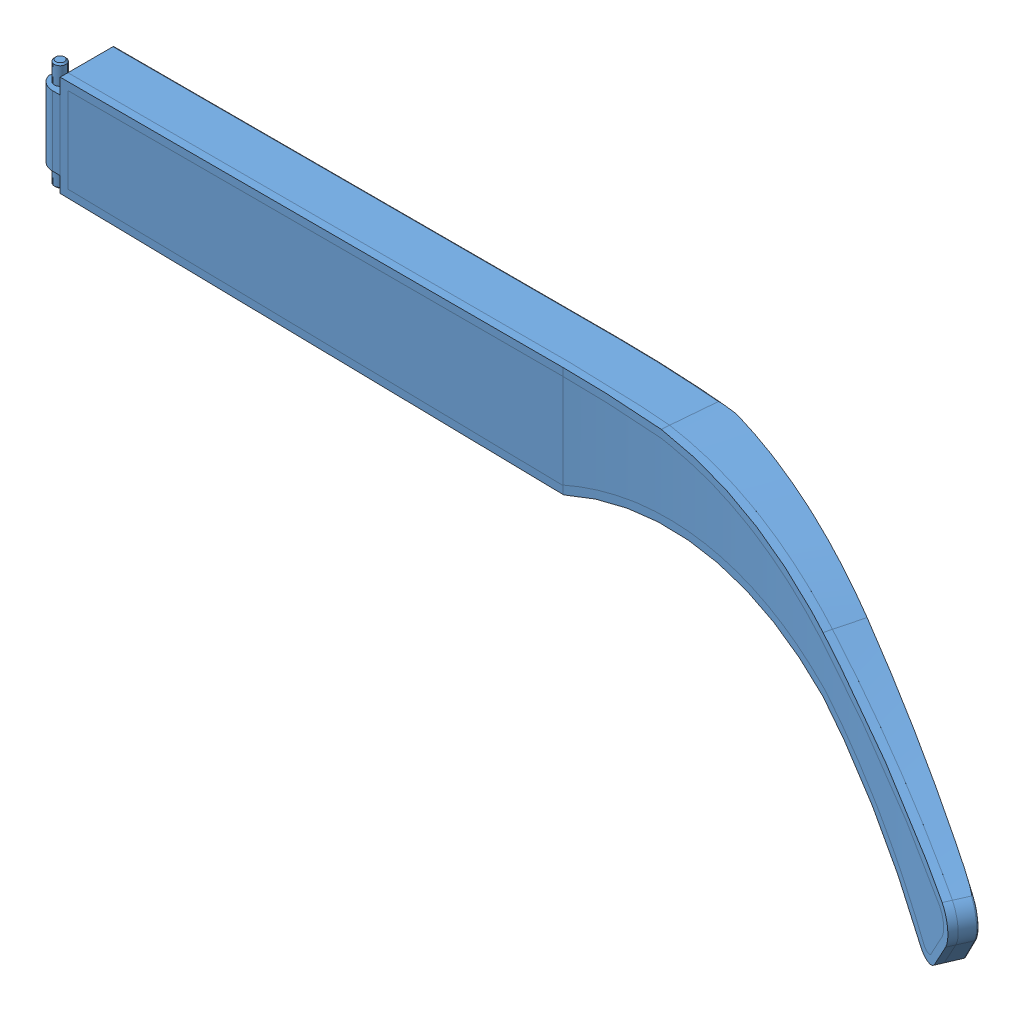
SolidWorks assembly Right assm, configuration Default. Lengths in mm.
Overall size (132.64 32.79 22.04).
2 component instances, 2 part files, 3 mates.
Components (placement in the parent):
- Right Arm-1: Right Arm [Default] at (75.3908 107.9453 69.6006) size (132.64 32.79 22.04)
- Speaker chamber-1: Speaker chamber [Default] at (75.1632 136.3366 18.1574) x (1 0 0) z (0 -1 0) size (14 4 6)
Mates (geometry in assembly coordinates):
- Coincident1: coincident: plane of Right Arm-1 through (5.3908 127.9453 22.1574) normal (0 0 -1); plane of Speaker chamber-1 through (75.1632 136.3366 22.1574) normal (0 0 1)
- Coincident3: coincident: line of Right Arm-1 through (64.5366 118.6849 22.1574) axis (1 0 0); plane of Speaker chamber-1 through (74.492 118.6849 22.1574) normal (0 1 0)
- Coincident4: coincident: line of Right Arm-1 through (74.492 118.6849 22.1574) axis (0 -1 0); plane of Speaker chamber-1 through (74.492 114.6849 22.1574) normal (1 0 0)
